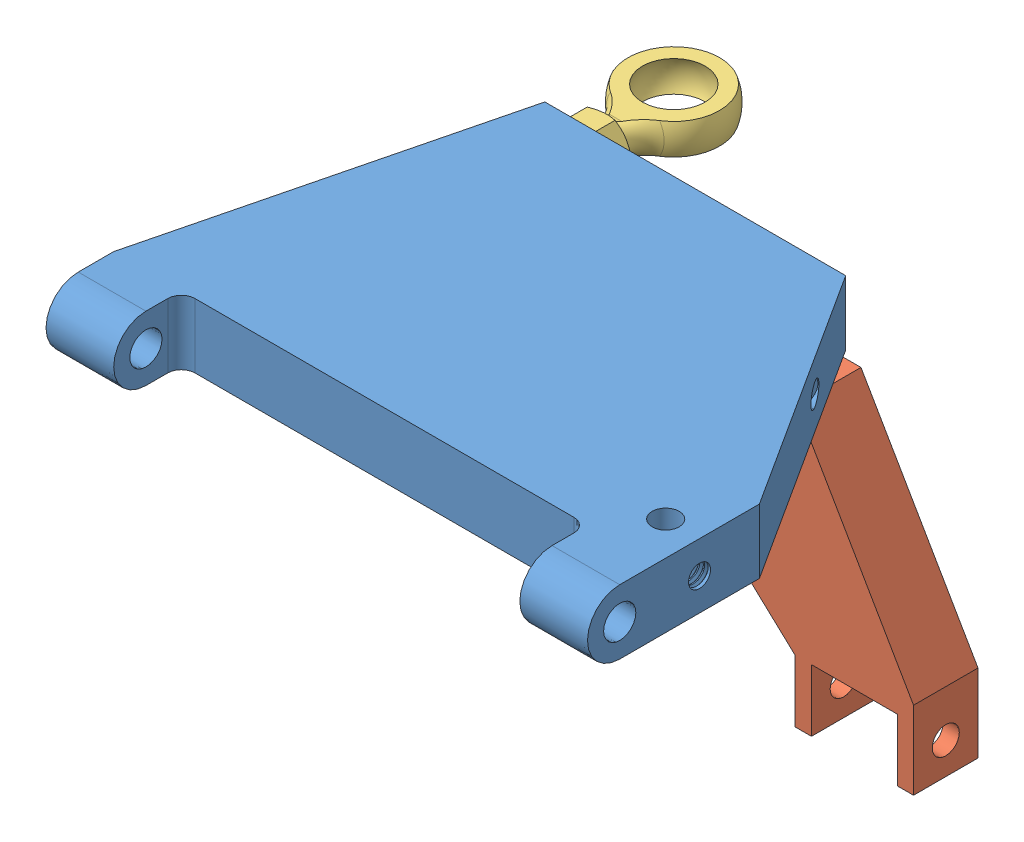
SolidWorks assembly lower wishbone, configuration Default. Lengths in mm.
Overall size (371.06 133 164.86).
3 component instances, 3 part files, 3 mates.
Components (placement in the parent):
- BottomWishbone-1: BottomWishbone [Default] at (-16.5922 169.1347 217.8381) size (371.06 96.39 152)
- BottomShock mount-1: BottomShock mount [Default] at (138.9828 188.1847 233.7131) x (0 0 -1) z (-1 0 0) size (19.05 113.95 175.99)
- 3-8-24 swivel-1: 3-8-24 swivel [Default] at (37.4281 235.9441 243.2311) x (-1 0 0) z (0 -1 0) size (28.57 68.61 16.22)
Mates (geometry in assembly coordinates):
- Concentric2: concentric aligned: circle of BottomWishbone-1; circle of 3-8-24 swivel-1
- Coincident3: coincident anti-aligned: plane of BottomWishbone-1 through (-16.5922 188.1847 217.8381) normal (0 0 -1); plane of 3-8-24 swivel-1 through (26.551 179.3708 217.8381) normal (0 0 1)
- Parallel2: parallel aligned: plane of BottomWishbone-1 through (-16.5922 169.1347 217.8381) normal (0 -1 0); plane of 3-8-24 swivel-1 through (32.6203 174.0956 174.9756) normal (0 -1 0)
